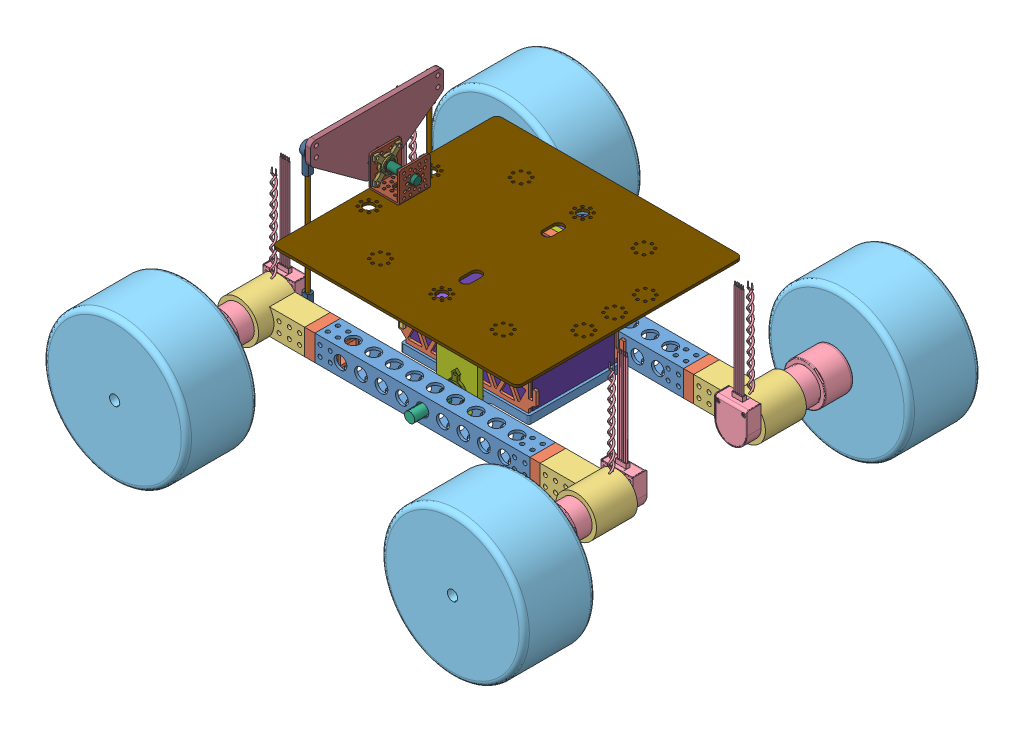
SolidWorks assembly Drivetrain sub assembly, configuration Default. Lengths in mm.
Overall size (596.9 285.85 566.52).
49 component instances, 21 part files, 71 mates.
Components (placement in the parent):
- One side drivetrain subassembly-1: One side drivetrain subassembly [Default] at (287.8049 327.7625 472.3662) size (596.9 246.35 221.71)
  - 10.5in box extrusion-1: 10.5in box extrusion [Default] at (70.3566 -7.0157 32.9173) size (266.7 31.75 31.75)
  - Extrusion to motor mount adapter-1: Extrusion to motor mount adapter [Default] at (108.4566 -10.1907 61.4923) x (0 0 1) z (-1 0 0) size (31.75 31.75 63.5)
  - Extrusion to motor mount adapter-2: Extrusion to motor mount adapter [Default] at (-234.4434 -10.1907 36.0923) x (0 0 -1) z (1 0 0) size (31.75 31.75 63.5)
  - Motor mount-1: Motor mount [Default] at (146.5566 -22.8907 13.8673) size (88.9 50.8 50.8)
  - Motor mount-2: Motor mount [Default] at (-272.5434 -22.8907 13.8673) x (-1 0 0) z (0 0 1) size (88.9 50.8 50.8)
  - GM9236S025-R1-SP_dc_motor_CAD-1: GM9236S025-R1-SP_dc_motor_CAD [Default] at (-272.5434 -22.8907 64.6673) size (52.61 175.4 145.51)
  - GM9236S025-R1-SP_dc_motor_CAD-2: GM9236S025-R1-SP_dc_motor_CAD [Default] at (146.5566 -22.8907 64.6673) size (52.61 175.4 145.51)
  - wheel-1: wheel [Default] at (146.5566 -31.2473 -139.2185) size (177.8 177.8 88.9)
  - wheel-2: wheel [Default] at (-272.5434 -31.2473 -139.2185) size (177.8 177.8 88.9)
- suspension shaft-1: suspension shaft [Default] at (224.8115 304.8719 616.4086) size (12.7 12.7 254)
- One side drivetrain subassembly-2: One side drivetrain subassembly [Default] at (161.8181 327.7625 760.4509) x (-1 0 0) z (0 0 -1) size (596.9 246.35 221.71)
  - 10.5in box extrusion-1: 10.5in box extrusion [Default] at (70.3566 -7.0157 32.9173) size (266.7 31.75 31.75)
  - Extrusion to motor mount adapter-1: Extrusion to motor mount adapter [Default] at (108.4566 -10.1907 61.4923) x (0 0 1) z (-1 0 0) size (31.75 31.75 63.5)
  - Extrusion to motor mount adapter-2: Extrusion to motor mount adapter [Default] at (-234.4434 -10.1907 36.0923) x (0 0 -1) z (1 0 0) size (31.75 31.75 63.5)
  - Motor mount-1: Motor mount [Default] at (146.5566 -22.8907 13.8673) size (88.9 50.8 50.8)
  - Motor mount-2: Motor mount [Default] at (-272.5434 -22.8907 13.8673) x (-1 0 0) z (0 0 1) size (88.9 50.8 50.8)
  - GM9236S025-R1-SP_dc_motor_CAD-1: GM9236S025-R1-SP_dc_motor_CAD [Default] at (-272.5434 -22.8907 64.6673) size (52.61 175.4 145.51)
  - GM9236S025-R1-SP_dc_motor_CAD-2: GM9236S025-R1-SP_dc_motor_CAD [Default] at (146.5566 -22.8907 64.6673) size (52.61 175.4 145.51)
  - wheel-1: wheel [Default] at (146.5566 -31.2473 -139.2185) size (177.8 177.8 88.9)
  - wheel-2: wheel [Default] at (-272.5434 -31.2473 -139.2185) size (177.8 177.8 88.9)
- Pillow Block-1: Pillow Block [Default] at (199.4115 279.4719 678.0036) size (50.8 127 6.35)
- L bracket 545400-1: L bracket 545400 [Default] at (224.8115 406.4719 703.4036) x (1 0 0) z (0 0 -1) size (25.4 31.76 31.75)
- Pillow Block-2: Pillow Block [Default] at (199.4115 279.4719 547.9556) size (50.8 127 6.35)
- L bracket 545400-2: L bracket 545400 [Default] at (224.8115 387.4219 547.9556) x (1 0 0) z (0 1 0) size (25.4 31.76 31.75)
- Back suspension assembly-1: Back suspension assembly [Default] at (-41.482 498.7048 750.9671) x (0 0 -1) z (0 -1 0) size (15.88 15.88 196.85)
  - 6in 10-32 threaded rod-1: 6in 10-32 threaded rod [Default] at (59.1522 88.4935 33.4954) size (4.83 4.83 152.4)
  - 60645K311_STEEL BALL JOINT ROD END 10-32-1: 60645K311_STEEL BALL JOINT ROD END 10-32 [60645K311] at (59.1522 88.4935 33.4954) x (1 0 0) z (0 1 0) size (15.88 34.93 10.12)
  - 60645K311_STEEL BALL JOINT ROD END 10-32-2: 60645K311_STEEL BALL JOINT ROD END 10-32 [60645K311] at (59.1522 88.4935 185.8954) x (0 -1 0) z (-1 0 0) size (15.88 34.93 10.12)
- Back suspension assembly-2: Back suspension assembly [Default] at (106.1637 279.314 452.5089) x (-1 0 0) z (0 1 0) size (15.88 15.88 196.85)
  - 6in 10-32 threaded rod-1: 6in 10-32 threaded rod [Default] at (59.1522 88.4935 33.4954) size (4.83 4.83 152.4)
  - 60645K311_STEEL BALL JOINT ROD END 10-32-1: 60645K311_STEEL BALL JOINT ROD END 10-32 [60645K311] at (59.1522 88.4935 33.4954) x (1 0 0) z (0 1 0) size (15.88 34.93 10.12)
  - 60645K311_STEEL BALL JOINT ROD END 10-32-2: 60645K311_STEEL BALL JOINT ROD END 10-32 [60645K311] at (59.1522 88.4935 185.8954) x (0 -1 0) z (-1 0 0) size (15.88 34.93 10.12)
- 1.5in c channel-1: 1.5in c channel [Default] at (66.0615 417.2669 597.1046) size (38.1 38.1 38.1)
- 3-8in pillow block bearing 535114 -1: 3-8in pillow block bearing 535114  [Default] at (115.9851 426.8538 588.5679) x (0 1 0) z (0 0 1) size (33.27 5.09 33.27)
- 3-8in pillow block bearing 535114 -2: 3-8in pillow block bearing 535114  [Default] at (54.2379 445.7799 588.5679) x (0 -1 0) z (0 0 1) size (33.27 5.09 33.27)
- Back connector for suspension-1: Back connector for suspension [Default] at (50.9802 455.3669 616.1546) x (0 0 -1) z (1 0 0) size (165.1 76.2 6.35)
- .375in clamping hub 545596-1: .375in clamping hub 545596 [Default] at (63.5726 455.3706 576.3886) x (0 0.707107 -0.707107) z (0 0.707107 0.707107) size (20.57 9.53 26.29)
- .375in shaft for suspension-1: .375in shaft for suspension [Default] at (107.4952 436.3169 616.1546) x (0 0 1) z (-1 0 0) size (9.53 9.53 63.5)
- .5in pillow block-1: .5in pillow block [Default] at (242.6528 280.56 562.5936) x (0.707107 0.707107 0) z (-0.707107 0.707107 0) size (33.27 5.09 33.27)
- .5in pillow block-2: .5in pillow block [Default] at (242.6528 329.1837 669.7156) x (0.707107 -0.707107 0) z (-0.707107 -0.707107 0) size (33.27 5.09 33.27)
- .5in pillow block-3: .5in pillow block [Default] at (242.6528 280.56 692.6416) x (0.707107 0.707107 0) z (-0.707107 0.707107 0) size (33.27 5.09 33.27)
- .5in pillow block-4: .5in pillow block [Default] at (242.6528 329.1837 539.6676) x (0.707107 -0.707107 0) z (-0.707107 -0.707107 0) size (33.27 5.09 33.27)
- 12V 16Ah Battery-1: 12V 16Ah Battery [Default] at (149.8195 410.3743 667.1547) x (0 1 0) z (1 0 0) size (99 102 151)
- Top plate 2-1: Top plate 2 [Default] at (66.0615 414.0919 476.4546) x (0 0 -1) z (0 1 0) size (279.4 304.8 3.17)
- battery mount-1: battery mount [Default] at (304.1865 311.3743 674.8286) x (0 0 1) z (-1 0 0) size (117.35 30.33 158.75)
- battery mount 2-1: battery mount 2 [Default] at (205.7615 406.4719 678.0036) x (-1 0 0) z (0 0 -1) size (171.07 95.22 9.26)
- battery mount 2-2: battery mount 2 [Default] at (243.8615 406.4719 554.3056) size (171.07 95.22 9.26)
- battery holder door-1: battery holder door [Default] at (144.041 361.2573 616.1546) x (0 0 -1) z (1 0 0) size (117.88 52.39 4.51)
Mates (geometry in assembly coordinates):
- Concentric1: concentric anti-aligned: cylinder of One side drivetrain subassembly-1/10.5in box extrusion-1 through (224.8115 304.8719 505.2836) axis (0 0 1) radius 7.9375; cylinder of suspension shaft-1 through (224.8115 304.8719 743.4086) axis (0 0 -1) radius 6.35
- Distance1: distance = 15.875 mm aligned: plane of suspension shaft-1 through (224.8115 304.8719 489.4086) normal (0 0 -1); plane of One side drivetrain subassembly-1/10.5in box extrusion-1 through (358.1615 320.7469 505.2836) normal (0 0 -1)
- Parallel1: parallel aligned: plane of One side drivetrain subassembly-1/10.5in box extrusion-1 through (358.1615 320.7469 537.0336) normal (0 1 0); plane of One side drivetrain subassembly-2/10.5in box extrusion-1 through (91.4615 320.7469 695.7836) normal (0 1 0)
- Distance6: distance = 3.556 mm anti-aligned: plane of 0.5in shaft collar-2 through (224.8115 304.8719 501.7276) normal (0 0 1); plane of One side drivetrain subassembly-1/10.5in box extrusion-1 through (358.1615 320.7469 505.2836) normal (0 0 -1)
- Parallel3: parallel aligned: plane of One side drivetrain subassembly-1/10.5in box extrusion-1 through (358.1615 320.7469 537.0336) normal (0 1 0); plane of Pillow Block-2 through (199.4115 406.4719 554.3056) normal (0 1 0)
- Concentric28: concentric anti-aligned: circle of One side drivetrain subassembly-1/Motor mount-2; circle of Back suspension assembly-2/60645K311_STEEL BALL JOINT ROD END 10-32-1
- Coincident17: coincident anti-aligned: plane of One side drivetrain subassembly-1/Motor mount-2 through (15.2615 304.8719 537.0336) normal (0 0 1); plane of Back suspension assembly-2/60645K311_STEEL BALL JOINT ROD END 10-32-1 through (54.949 290.5844 537.0336) normal (0 0 -1)
- Parallel4: parallel aligned: plane of One side drivetrain subassembly-1/Motor mount-2 through (35.0894 320.7469 505.2836) normal (0 1 0); plane of Back suspension assembly-2/60645K311_STEEL BALL JOINT ROD END 10-32-1 through (41.8553 325.5094 541.0023) normal (0 1 0)
- Concentric2: concentric aligned: cylinder of suspension shaft-1 through (224.8115 304.8719 743.4086) axis (0 0 -1) radius 6.35; cylinder of One side drivetrain subassembly-2/10.5in box extrusion-1 through (224.8115 304.8719 727.5336) axis (0 0 -1) radius 7.9375
- Distance2: distance = 15.875 mm aligned: plane of suspension shaft-1 through (224.8115 304.8719 743.4086) normal (0 0 1); plane of One side drivetrain subassembly-2/10.5in box extrusion-1 through (91.4615 320.7469 727.5336) normal (0 0 1)
- Concentric3: concentric aligned: cylinder of suspension shaft-1 through (224.8115 304.8719 743.4086) axis (0 0 -1) radius 6.35; cylinder of 0.5in shaft collar-1 through (224.8115 304.8719 742.1386) axis (0 0 -1) radius 6.35
- Concentric6: concentric aligned: cylinder of suspension shaft-1 through (224.8115 304.8719 743.4086) axis (0 0 -1) radius 6.35; cylinder of 0.5in shaft collar-2 through (224.8115 304.8719 501.7276) axis (0 0 -1) radius 6.35
- Concentric7: concentric aligned: cylinder of suspension shaft-1 through (224.8115 304.8719 743.4086) axis (0 0 -1) radius 6.35; cylinder of Pillow Block-1 through (224.8115 304.8719 684.3536) axis (0 0 -1) radius 9.525
- Concentric10: concentric aligned: cylinder of suspension shaft-1 through (224.8115 304.8719 743.4086) axis (0 0 -1) radius 6.35; cylinder of Pillow Block-2 through (224.8115 304.8719 554.3056) axis (0 0 -1) radius 9.525
- Concentric57: concentric anti-aligned: cylinder of suspension shaft-1 through (224.8115 304.8719 743.4086) axis (0 0 -1) radius 6.35; cylinder of battery mount-1 through (224.8115 304.8719 520.1426) axis (0 0 1) radius 6.477
- Distance3: distance = 3.556 mm anti-aligned: plane of 0.5in shaft collar-1 through (224.8115 304.8719 731.0896) normal (0 0 -1); plane of One side drivetrain subassembly-2/10.5in box extrusion-1 through (91.4615 320.7469 727.5336) normal (0 0 1)
- Parallel2: parallel aligned: plane of One side drivetrain subassembly-2/10.5in box extrusion-1 through (91.4615 320.7469 695.7836) normal (0 1 0); plane of Pillow Block-1 through (199.4115 406.4719 684.3536) normal (0 1 0)
- Concentric27: concentric anti-aligned: cylinder of One side drivetrain subassembly-2/Motor mount-1 through (47.0115 298.5219 727.5336) axis (0 0 -1) radius 2.5082; circle of Back suspension assembly-1/60645K311_STEEL BALL JOINT ROD END 10-32-2
- Coincident16: coincident anti-aligned: plane of One side drivetrain subassembly-2/Motor mount-1 through (15.2615 304.8719 695.7836) normal (0 0 -1); plane of Back suspension assembly-1/60645K311_STEEL BALL JOINT ROD END 10-32-2 through (54.949 290.5844 695.7836) normal (0 0 1)
- Parallel5: parallel aligned: plane of One side drivetrain subassembly-2/Motor mount-1 through (35.0894 320.7469 727.5336) normal (0 1 0); plane of Back suspension assembly-1/60645K311_STEEL BALL JOINT ROD END 10-32-2 through (41.8553 325.5094 691.8148) normal (0 1 0)
- Distance13: distance = 11.43 mm anti-aligned: plane of Pillow Block-1 through (199.4115 279.4719 684.3536) normal (0 0 1); plane of One side drivetrain subassembly-2/10.5in box extrusion-1 through (91.4615 320.7469 695.7836) normal (0 0 -1)
- Coincident32: coincident anti-aligned: plane of Pillow Block-1 through (199.4115 279.4719 684.3536) normal (0 0 1); plane of .5in pillow block-2 through (224.8115 304.8719 684.3536) normal (0 0 -1)
- Concentric45: concentric aligned: cylinder of Pillow Block-1 through (205.7615 304.8719 678.0036) axis (0 0 1) radius 1.778; cylinder of .5in pillow block-2 through (205.7615 304.8719 687.5286) axis (0 0 1) radius 1.778
- Concentric46: concentric aligned: cylinder of Pillow Block-1 through (224.8115 323.9219 678.0036) axis (0 0 1) radius 1.778; cylinder of .5in pillow block-2 through (224.8115 323.9219 687.5286) axis (0 0 1) radius 1.778
- Coincident34: coincident anti-aligned: plane of Pillow Block-1 through (199.4115 279.4719 678.0036) normal (0 0 -1); plane of .5in pillow block-3 through (224.8115 304.8719 678.0036) normal (0 0 1)
- Concentric47: concentric anti-aligned: cylinder of Pillow Block-1 through (224.8115 323.9219 678.0036) axis (0 0 1) radius 1.778; cylinder of .5in pillow block-3 through (224.8115 323.9219 674.8286) axis (0 0 -1) radius 1.778
- Concentric48: concentric anti-aligned: cylinder of Pillow Block-1 through (243.8615 304.8719 678.0036) axis (0 0 1) radius 1.778; cylinder of .5in pillow block-3 through (243.8615 304.8719 674.8286) axis (0 0 -1) radius 1.778
- Coincident38: coincident anti-aligned: plane of Pillow Block-1 through (199.4115 279.4719 684.3536) normal (0 0 1); plane of L bracket 545400-1 through (224.8115 438.2219 684.3536) normal (0 0 -1)
- Concentric53: concentric aligned: cylinder of Pillow Block-1 through (224.8115 387.4219 684.3536) axis (0 0 -1) radius 6.35; cylinder of L bracket 545400-1 through (224.8115 387.4219 684.3536) axis (0 0 -1) radius 6.3627
- Concentric54: concentric anti-aligned: cylinder of Pillow Block-1 through (231.7263 394.3367 678.0036) axis (0 0 1) radius 1.778; cylinder of L bracket 545400-1 through (231.7263 394.3367 684.3536) axis (0 0 -1) radius 1.778
- Concentric59: concentric aligned: cylinder of Pillow Block-1 through (224.8115 387.4219 684.3536) axis (0 0 -1) radius 6.35; cylinder of battery mount 2-1 through (224.8115 387.4219 679.5911) axis (0 0 -1) radius 6.35
- Coincident48: coincident anti-aligned: plane of Pillow Block-1 through (199.4115 279.4719 678.0036) normal (0 0 -1); plane of battery mount 2-1 through (205.7615 406.4719 678.0036) normal (0 0 1)
- Parallel8: parallel aligned: plane of Pillow Block-1 through (250.2115 279.4719 684.3536) normal (1 0 0); plane of battery mount 2-1 through (243.8615 406.4719 668.7453) normal (1 0 0)
- Concentric56: concentric anti-aligned: cylinder of L bracket 545400-1 through (224.8115 401.3919 703.4036) axis (0 -1 0) radius 6.3627; cylinder of Top plate 2-1 through (224.8115 414.0919 703.4036) axis (0 1 0) radius 6.35
- Distance10: distance = 7.62 mm anti-aligned: plane of Top plate 2-1 through (66.0615 414.0919 476.4546) normal (0 -1 0); plane of L bracket 545400-1 through (224.8115 406.4719 703.4036) normal (0 1 0)
- Concentric11: concentric aligned: cylinder of Pillow Block-2 through (224.8115 387.4219 554.3056) axis (0 0 -1) radius 6.35; cylinder of L bracket 545400-2 through (224.8115 387.4219 542.8756) axis (0 0 -1) radius 6.3627
- Coincident8: coincident anti-aligned: plane of Pillow Block-2 through (199.4115 279.4719 547.9556) normal (0 0 -1); plane of L bracket 545400-2 through (224.8115 387.4219 547.9556) normal (0 0 1)
- Coincident30: coincident anti-aligned: plane of Pillow Block-2 through (199.4115 279.4719 547.9556) normal (0 0 -1); plane of .5in pillow block-1 through (224.8115 304.8719 547.9556) normal (0 0 1)
- Concentric43: concentric anti-aligned: cylinder of Pillow Block-2 through (224.8115 285.8219 547.9556) axis (0 0 1) radius 1.778; cylinder of .5in pillow block-1 through (224.8115 285.8219 544.7806) axis (0 0 -1) radius 1.778
- Concentric44: concentric anti-aligned: cylinder of Pillow Block-2 through (224.8115 323.9219 547.9556) axis (0 0 1) radius 1.778; cylinder of .5in pillow block-1 through (224.8115 323.9219 544.7806) axis (0 0 -1) radius 1.778
- Coincident35: coincident anti-aligned: plane of Pillow Block-2 through (199.4115 279.4719 554.3056) normal (0 0 1); plane of .5in pillow block-4 through (224.8115 304.8719 554.3056) normal (0 0 -1)
- Concentric49: concentric aligned: cylinder of Pillow Block-2 through (243.8615 304.8719 547.9556) axis (0 0 1) radius 1.778; cylinder of .5in pillow block-4 through (243.8615 304.8719 557.4806) axis (0 0 1) radius 1.778
- Concentric50: concentric aligned: cylinder of Pillow Block-2 through (224.8115 285.8219 547.9556) axis (0 0 1) radius 1.778; cylinder of .5in pillow block-4 through (224.8115 285.8219 557.4806) axis (0 0 1) radius 1.778
- Concentric52: concentric anti-aligned: cylinder of Pillow Block-2 through (231.7263 394.3367 547.9556) axis (0 0 1) radius 1.778; cylinder of L bracket 545400-2 through (231.7263 394.3367 542.8756) axis (0 0 -1) radius 1.778
- Coincident51: coincident anti-aligned: plane of Pillow Block-2 through (199.4115 279.4719 554.3056) normal (0 0 1); plane of battery mount 2-2 through (243.8615 406.4719 554.3056) normal (0 0 -1)
- Concentric60: concentric anti-aligned: cylinder of Pillow Block-2 through (224.8115 387.4219 554.3056) axis (0 0 -1) radius 6.35; cylinder of battery mount 2-2 through (224.8115 387.4219 552.7181) axis (0 0 1) radius 6.35
- Parallel9: parallel aligned: plane of Pillow Block-2 through (250.2115 279.4719 554.3056) normal (1 0 0); plane of battery mount 2-2 through (243.8615 406.4719 563.5639) normal (1 0 0)
- Concentric55: concentric aligned: cylinder of L bracket 545400-2 through (224.8115 406.4719 528.9056) axis (0 1 0) radius 6.3627; cylinder of Top plate 2-1 through (224.8115 414.0919 528.9056) axis (0 1 0) radius 6.35
- Coincident23: coincident anti-aligned: plane of Back suspension assembly-2/60645K311_STEEL BALL JOINT ROD END 10-32-2 through (50.9802 487.4344 548.9398) normal (1 0 0); plane of Back connector for suspension-1 through (50.9802 455.3669 616.1546) normal (-1 0 0)
- Coincident21: coincident anti-aligned: plane of 1.5in c channel-1 through (68.3475 455.3669 635.2046) normal (1 0 0); plane of 3-8in pillow block bearing 535114 -2 through (68.3475 436.3169 616.1546) normal (-1 0 0)
- Concentric30: concentric aligned: cylinder of 1.5in c channel-1 through (104.1615 449.7873 629.625) axis (1 0 0) radius 1.778; cylinder of 3-8in pillow block bearing 535114 -2 through (71.5225 449.7873 629.625) axis (1 0 0) radius 1.778
- Concentric31: concentric aligned: cylinder of 1.5in c channel-1 through (104.1615 422.8465 602.6842) axis (1 0 0) radius 1.778; cylinder of 3-8in pillow block bearing 535114 -2 through (71.5225 422.8465 602.6842) axis (1 0 0) radius 1.778
- Coincident22: coincident anti-aligned: plane of 1.5in c channel-1 through (101.8755 419.5529 635.2046) normal (-1 0 0); plane of 3-8in pillow block bearing 535114 -1 through (101.8755 436.3169 616.1546) normal (1 0 0)
- Concentric32: concentric anti-aligned: cylinder of 1.5in c channel-1 through (104.1615 449.7873 602.6842) axis (1 0 0) radius 1.778; cylinder of 3-8in pillow block bearing 535114 -1 through (98.7005 449.7873 602.6842) axis (-1 0 0) radius 1.778
- Concentric33: concentric anti-aligned: cylinder of 1.5in c channel-1 through (104.1615 422.8465 629.625) axis (1 0 0) radius 1.778; cylinder of 3-8in pillow block bearing 535114 -1 through (98.7005 422.8465 629.625) axis (-1 0 0) radius 1.778
- Coincident65: coincident anti-aligned: plane of 1.5in c channel-1 through (104.1615 417.2669 635.2046) normal (0 -1 0); plane of Top plate 2-1 through (66.0615 417.2669 476.4546) normal (0 1 0)
- Concentric61: concentric anti-aligned: cylinder of 1.5in c channel-1 through (85.1115 417.2669 616.1546) axis (0 -1 0) radius 6.3627; cylinder of Top plate 2-1 through (85.1115 414.0919 616.1546) axis (0 1 0) radius 6.35
- Concentric51: concentric aligned: cylinder of 3-8in pillow block bearing 535114 -1 through (96.7891 436.3169 616.1546) axis (1 0 0) radius 4.7625; cylinder of .375in shaft for suspension-1 through (43.9952 436.3169 616.1546) axis (1 0 0) radius 4.7625
- Coincident24: coincident anti-aligned: plane of Back connector for suspension-1 through (50.9802 455.3669 616.1546) normal (-1 0 0); plane of .375in clamping hub 545596-1 through (50.9802 436.3169 616.1546) normal (1 0 0)
- Concentric41: concentric anti-aligned: cylinder of Back connector for suspension-1 through (57.3302 436.3169 616.1546) axis (-1 0 0) radius 6.35; cylinder of .375in clamping hub 545596-1 through (53.5202 436.3169 616.1546) axis (1 0 0) radius 4.7625
- Concentric42: concentric anti-aligned: cylinder of Back connector for suspension-1 through (57.3302 436.3169 625.9336) axis (-1 0 0) radius 1.778; circle of .375in clamping hub 545596-1
- Coincident28: coincident aligned: plane of .375in clamping hub 545596-1 through (43.9952 436.3169 616.1546) normal (-1 0 0); plane of .375in shaft for suspension-1 through (43.9952 436.3169 616.1546) normal (-1 0 0)
- Coincident29: coincident anti-aligned: circle of .375in clamping hub 545596-1; circle of .375in shaft for suspension-1
- Coincident40: coincident anti-aligned: plane of .5in pillow block-3 through (224.8115 304.8719 674.8286) normal (0 0 -1); plane of battery mount-1 through (145.4365 311.3743 674.8286) normal (0 0 1)
- Coincident42: coincident anti-aligned: plane of 12V 16Ah Battery-1 through (300.8195 311.3743 667.1547) normal (0 -1 0); plane of battery mount-1 through (145.4365 311.3743 674.8286) normal (0 1 0)
- Distance11: distance = 7.6741 mm aligned: plane of 12V 16Ah Battery-1 through (300.8195 410.3743 565.1547) normal (0 0 -1); plane of battery mount-1 through (145.4365 311.3743 557.4806) normal (0 0 -1)
- Coincident50: coincident aligned: plane of 12V 16Ah Battery-1 through (300.8195 410.3743 667.1547) normal (1 0 0); plane of battery mount 2-1 through (300.8195 406.4719 671.9203) normal (1 0 0)
- Parallel6: parallel anti-aligned: plane of Top plate 2-1 through (66.0615 414.0919 476.4546) normal (0 -1 0); plane of battery mount-1 through (145.4365 311.3743 674.8286) normal (0 1 0)
- Coincident53: coincident anti-aligned: plane of battery mount 2-1 through (144.041 327.0969 668.7453) normal (1 0 0); plane of battery holder door-1 through (144.041 361.2573 616.1546) normal (-1 0 0)
- Coincident54: coincident anti-aligned: plane of battery mount 2-1 through (144.041 327.0969 668.7453) normal (0 1 0); plane of battery holder door-1 through (148.5495 327.0969 563.5639) normal (0 -1 0)
- Coincident55: coincident anti-aligned: plane of battery mount 2-1 through (205.7615 406.4719 668.7453) normal (0 0 -1); plane of battery holder door-1 through (148.5495 327.0969 668.7453) normal (0 0 1)
